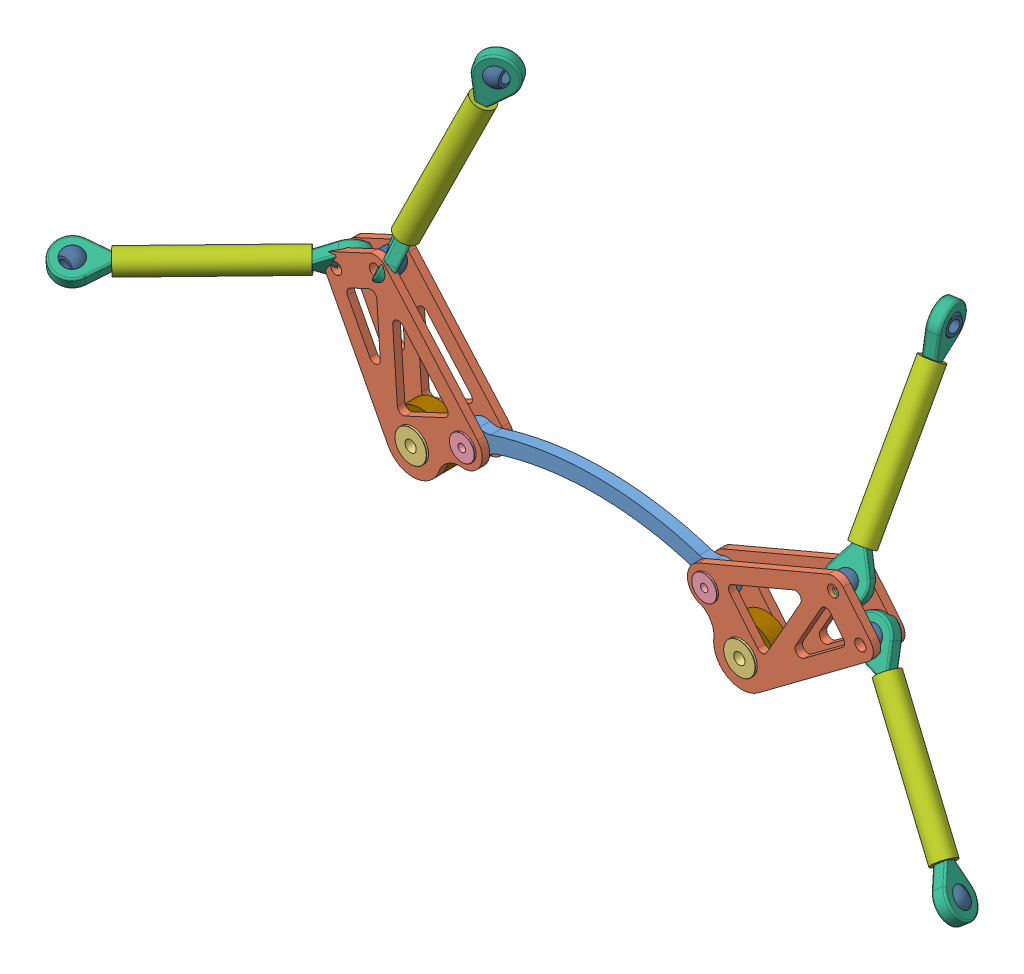
SolidWorks assembly 连杆完整装配, configuration 默认. Lengths in mm.
Overall size (460.39 243.47 165.33).
47 component instances, 10 part files, 72 mates.
Components (placement in the parent):
- 连杆-1: 连杆 [默认] at origin size (146 24.15 6)
- DP_连杆转接板_1 - 副本-1: DP_连杆转接板_1 - 副本 [默认] at (-122.9597 53.5693 -5.5) x (-0.906944 -0.421252 0) z (0 0 1) size (58.5 95 4)
- DP_法兰轴承6x15x5-1: DP_法兰轴承6x15x5 [默认] at (-92.2083 -12.6376 7.7) x (0.813191 0.581997 0) z (0.581997 -0.813191 0) size (17 5 17)
- DP_法兰轴承6x15x5-2: DP_法兰轴承6x15x5 [默认] at (84.0719 -23.1573 7.7) x (0.813191 0.581997 0) z (0.581997 -0.813191 0) size (17 5 17)
- DP_法兰轴承6x15x5-3: DP_法兰轴承6x15x5 [默认] at (-92.2083 -12.6376 -1.7) x (0.663783 0.747925 0) z (-0.747925 0.663783 0) size (17 5 17)
- DP_法兰轴承6x15x5-4: DP_法兰轴承6x15x5 [默认] at (84.0719 -23.1573 -1.7) x (0.621529 0.783391 0) z (-0.783391 0.621529 0) size (17 5 17)
- DP_连杆转接板_1 - 副本-2: DP_连杆转接板_1 - 副本 [默认] at (-122.9597 53.5693 7.5) x (-0.906944 -0.421252 0) z (0 0 1) size (58.5 95 4)
- DP_法兰轴承4x12x4-1: DP_法兰轴承4x12x4 [默认] at (-65 0 8.5) x (0.974596 0.223969 0) z (0.223969 -0.974596 0) size (13.5 4 13.5)
- DP_法兰轴承4x12x4-2: DP_法兰轴承4x12x4 [默认] at (65 0 8.5) x (0.8189 0.573936 0) z (0.573936 -0.8189 0) size (13.5 4 13.5)
- DP_法兰轴承4x12x4-3: DP_法兰轴承4x12x4 [默认] at (65 0 -2.5) x (-0.752362 -0.65875 0) z (0.65875 -0.752362 0) size (13.5 4 13.5)
- DP_法兰轴承4x12x4-4: DP_法兰轴承4x12x4 [默认] at (-65 0 -2.5) x (0.992638 -0.121118 0) z (0.121118 0.992638 0) size (13.5 4 13.5)
- MF84ZZ-1: MF84ZZ [默认] at (-65 0 3.5) x (0 0 1) z (-0.99056 0.137078 0) size (3 9.2 9.2)
- MF84ZZ-2: MF84ZZ [默认] at (65 0 3.5) x (0 0 1) z (-0.982047 0.188634 0) size (3 9.2 9.2)
- MF84ZZ-3: MF84ZZ [默认] at (65 0 2.5) x (0 0 -1) z (0.978579 0.205871 0) size (3 9.2 9.2)
- MF84ZZ-4: MF84ZZ [默认] at (-65 0 2.5) x (0 0 -1) z (0.939447 0.342693 0) size (3 9.2 9.2)
- DP_连杆转接板_1 - 副本-5: DP_连杆转接板_1 - 副本 [默认] at (140.4214 23.2511 11.5) x (0.635732 -0.77191 0) z (0 0 -1) size (58.5 95 4)
- DP_连杆转接板_1 - 副本-6: DP_连杆转接板_1 - 副本 [默认] at (140.4214 23.2511 -1.5) x (0.635732 -0.77191 0) z (0 0 -1) size (58.5 95 4)
- 底盘-连杆系统-1: 底盘-连杆系统 [默认] at (-112.5298 58.4137 3) x (0.523124 -0.035021 0.851537) z (0.360356 0.914535 -0.183765) size (20 20 126) (flexible)
  - 鱼眼轴承M6-1: 鱼眼轴承M6 [默认] at origin size (20 6.75 46)
  - 铝柱 M6-1: 铝柱 M6 [默认] at (0 0 15) x (0.271087 -0.962555 0) z (0 0 1) size (12 12 76)
  - 鱼眼轴承M6-2: 鱼眼轴承M6 [默认] at (0 0 106) x (0 -1 0) z (0 0 -1) size (20 6.75 46)
- 铝合金垫柱4.1D6X2-1: 铝合金垫柱4.1D6X2 [默认] at (65 0 -2.5) size (6 6 2)
- 铝合金垫柱4.1D6X2-2: 铝合金垫柱4.1D6X2 [默认] at (-65 0 -2.5) size (6 6 2)
- 铝合金垫柱4.1D6X2-3: 铝合金垫柱4.1D6X2 [默认] at (65 0 6.5) size (6 6 2)
- 铝合金垫柱4.1D6X2-4: 铝合金垫柱4.1D6X2 [默认] at (-65 0 6.5) size (6 6 2)
- 底盘-连杆系统-2: 底盘-连杆系统 [默认] at (-133.3896 48.7249 3) x (-0.267385 -0.913473 -0.306712) z (-0.718743 -0.022937 0.694898) size (20 20 126) (flexible)
  - 鱼眼轴承M6-1: 鱼眼轴承M6 [默认] at origin size (20 6.75 46)
  - 铝柱 M6-1: 铝柱 M6 [默认] at (0 0 15) x (0.248789 0.968558 0) z (0 0 1) size (12 12 76)
  - 鱼眼轴承M6-2: 鱼眼轴承M6 [默认] at (0 0 106) x (0 -1 0) z (0 0 -1) size (20 6.75 46)
- 底盘-连杆系统-3: 底盘-连杆系统 [默认] at (133.1105 32.1281 3) x (-0.96943 0.077155 0.232923) z (-0.068591 0.826217 -0.559161) size (20 20 126) (flexible)
  - 鱼眼轴承M6-1: 鱼眼轴承M6 [默认] at origin size (20 6.75 46)
  - 铝柱 M6-1: 铝柱 M6 [默认] at (0 0 15) x (-0.636531 -0.771251 0) z (0 0 1) size (12 12 76)
  - 鱼眼轴承M6-2: 鱼眼轴承M6 [默认] at (0 0 106) x (0 -1 0) z (0 0 -1) size (20 6.75 46)
- 底盘-连杆系统-4: 底盘-连杆系统 [默认] at (219.7551 -57.5337 32.6306) x (0.067529 0.437189 0.896831) z (-0.679461 0.678376 -0.279534) size (20 20 126) (flexible)
  - 鱼眼轴承M6-1: 鱼眼轴承M6 [默认] at origin size (20 6.75 46)
  - 铝柱 M6-1: 铝柱 M6 [默认] at (0 0 15) x (0.188345 -0.982103 0) z (0 0 1) size (12 12 76)
  - 鱼眼轴承M6-2: 鱼眼轴承M6 [默认] at (0 0 106) x (0 -1 0) z (0 0 -1) size (20 6.75 46)
- 打印件1-1: 打印件1 [默认] at (84.0719 -23.1573 -1.5) size (30 30 9)
- 打印件1-2: 打印件1 [默认] at (-92.2083 -12.6376 -1.5) size (30 30 9)
- 鱼眼轴承内圈-2: 鱼眼轴承内圈 [默认] at (-133.3896 48.7249 3) x (0 0 -1) z (0.969663 0.244444 0) size (9 12.7 12.7)
- 鱼眼轴承内圈-3: 鱼眼轴承内圈 [默认] at (-112.5298 58.4137 3) x (0 0 1) z (-0.902121 0.431484 0) size (9 12.7 12.7)
- 鱼眼轴承内圈-4: 鱼眼轴承内圈 [默认] at (-74.3322 155.3544 -16.4791) size (9 12.7 12.7)
- 鱼眼轴承内圈-5: 鱼眼轴承内圈 [默认] at (125.8398 119.7071 -56.271) size (9 12.7 12.7)
- 鱼眼轴承内圈-6: 鱼眼轴承内圈 [默认] at (133.1105 32.1281 3) x (0 0 1) z (-0.999574 0.029184 0) size (9 12.7 12.7)
- 鱼眼轴承内圈-7: 鱼眼轴承内圈 [默认] at (147.7323 14.3741 3) x (0 0 1) z (-0.983588 0.18043 0) size (9 12.7 12.7)
- 鱼眼轴承内圈-8: 鱼眼轴承内圈 [默认] at (219.7551 -57.5337 32.6306) x (-0.216884 -0.288424 0.932616) z (-0.939281 0.321897 -0.118883) size (9 12.7 12.7)
- 鱼眼轴承内圈-9: 鱼眼轴承内圈 [默认] at (-209.5763 46.2936 76.6592) x (0 0 -1) z (0.998632 -0.05228 0) size (9 12.7 12.7)
Mates (geometry in assembly coordinates):
- 同心5: concentric aligned: cylinder of DP_连杆转接板_1 - 副本-1 through (-92.2083 -12.6376 -1.5) axis (0 0 -1) radius 7.5; cylinder of DP_连杆转接板_1 - 副本-2 through (-92.2083 -12.6376 11.5) axis (0 0 -1) radius 7.5
- 重合5: coincident aligned: plane of DP_法兰轴承6x15x5-1 through (-89.7687 -10.8916 12.7) normal (0 0 1); plane of DP_法兰轴承6x15x5-2 through (86.5115 -21.4113 12.7) normal (0 0 1)
- 重合6: coincident aligned: plane of DP_法兰轴承6x15x5-3 through (-90.217 -10.3938 -6.7) normal (0 0 -1); plane of DP_法兰轴承6x15x5-4 through (85.9365 -20.8071 -6.7) normal (0 0 -1)
- 重合7: coincident aligned: plane of DP_法兰轴承4x12x4-1 through (-59.1524 1.3438 8.5) normal (0 0 -1); plane of DP_法兰轴承4x12x4-2 through (69.9134 3.4436 8.5) normal (0 0 -1)
- 重合8: coincident aligned: plane of DP_法兰轴承4x12x4-3 through (60.4858 -3.9525 -2.5) normal (0 0 1); plane of DP_法兰轴承4x12x4-4 through (-59.0442 -0.7267 -2.5) normal (0 0 1)
- 同心8: concentric aligned: cylinder of DP_连杆转接板_1 - 副本-1 through (-65 0 -1.5) axis (0 0 -1) radius 6; cylinder of DP_连杆转接板_1 - 副本-2 through (-65 0 11.5) axis (0 0 -1) radius 6
- 同心9: concentric aligned: cylinder of DP_连杆转接板_1 - 副本-2 through (-65 0 11.5) axis (0 0 -1) radius 6; cylinder of DP_法兰轴承4x12x4-1 through (-65 0 8.5) axis (0 0 -1) radius 6
- 重合9: coincident anti-aligned: plane of DP_连杆转接板_1 - 副本-2 through (-112.5298 58.4137 11.5) normal (0 0 1); plane of DP_法兰轴承4x12x4-1 through (-58.4215 1.5118 11.5) normal (0 0 -1)
- 重合11: coincident anti-aligned: plane of DP_连杆转接板_1 - 副本-1 through (-112.5298 58.4137 -5.5) normal (0 0 -1); plane of DP_法兰轴承4x12x4-4 through (-58.2997 -0.8175 -5.5) normal (0 0 1)
- 同心11: concentric anti-aligned: cylinder of DP_连杆转接板_1 - 副本-1 through (-65 0 -1.5) axis (0 0 -1) radius 6; cylinder of DP_法兰轴承4x12x4-4 through (-65 0 -2.5) axis (0 0 1) radius 6
- 重合13: coincident anti-aligned: plane of DP_法兰轴承6x15x5-1 through (-85.2962 -7.6906 11.5) normal (0 0 -1); plane of DP_连杆转接板_1 - 副本-2 through (-112.5298 58.4137 11.5) normal (0 0 1)
- 同心13: concentric aligned: cylinder of DP_法兰轴承6x15x5-1 through (-92.2083 -12.6376 7.7) axis (0 0 -1) radius 7.5; cylinder of DP_连杆转接板_1 - 副本-2 through (-92.2083 -12.6376 11.5) axis (0 0 -1) radius 7.5
- 重合14: coincident anti-aligned: plane of DP_连杆转接板_1 - 副本-1 through (-112.5298 58.4137 -5.5) normal (0 0 -1); plane of DP_法兰轴承6x15x5-3 through (-86.5662 -6.2802 -5.5) normal (0 0 1)
- 同心15: concentric anti-aligned: circle of DP_连杆转接板_1 - 副本-1; circle of DP_法兰轴承6x15x5-3
- 重合15: coincident aligned: plane of MF84ZZ-1 through (-64.7258 1.9811 3.5) normal (0 0 -1); plane of MF84ZZ-2 through (65.3773 1.9641 3.5) normal (0 0 -1)
- 重合16: coincident aligned: plane of MF84ZZ-3 through (64.5883 1.9572 2.5) normal (0 0 1); plane of MF84ZZ-4 through (-65.6854 1.8789 2.5) normal (0 0 1)
- 重合17: coincident anti-aligned: plane of 连杆-1 through (0 0 6) normal (0 0 1); plane of MF84ZZ-2 through (65.7545 3.9282 6) normal (0 0 -1)
- 重合18: coincident anti-aligned: plane of 连杆-1 through (0 0 0) normal (0 0 -1); plane of MF84ZZ-3 through (64.1765 3.9143 0) normal (0 0 1)
- 同心17: concentric anti-aligned: cylinder of 连杆-1 through (-65 0 -9) axis (0 0 1) radius 4; cylinder of MF84ZZ-1 through (-65 0 3.5) axis (0 0 -1) radius 4
- 同心18: concentric anti-aligned: cylinder of 连杆-1 through (65 0 -9) axis (0 0 1) radius 4; cylinder of MF84ZZ-2 through (65 0 3.5) axis (0 0 -1) radius 2
- 同心19: concentric aligned: cylinder of 连杆-1 through (-65 0 -9) axis (0 0 1) radius 4; cylinder of MF84ZZ-4 through (-65 0 2.5) axis (0 0 1) radius 2
- 同心20: concentric aligned: circle of 连杆-1; cylinder of MF84ZZ-3 through (65 0 2.5) axis (0 0 1) radius 2
- 同心21: concentric aligned: cylinder of DP_法兰轴承4x12x4-1 through (-65 0 8.5) axis (0 0 -1) radius 2; cylinder of MF84ZZ-1 through (-65 0 3.5) axis (0 0 -1) radius 2
- 同心22: concentric aligned: cylinder of DP_法兰轴承4x12x4-2 through (65 0 8.5) axis (0 0 -1) radius 2; cylinder of MF84ZZ-2 through (65 0 3.5) axis (0 0 -1) radius 2
- 同心23: concentric anti-aligned: cylinder of DP_法兰轴承4x12x4-2 through (65 0 8.5) axis (0 0 -1) radius 6; cylinder of DP_连杆转接板_1 - 副本-5 through (65 0 7.5) axis (0 0 1) radius 6
- 重合19: coincident anti-aligned: plane of DP_法兰轴承4x12x4-2 through (70.5276 3.8741 11.5) normal (0 0 -1); plane of DP_连杆转接板_1 - 副本-5 through (133.1105 32.1281 11.5) normal (0 0 1)
- 同心24: concentric anti-aligned: cylinder of DP_法兰轴承6x15x5-2 through (84.0719 -23.1573 7.7) axis (0 0 -1) radius 7.5; cylinder of DP_连杆转接板_1 - 副本-5 through (84.0719 -23.1573 7.5) axis (0 0 1) radius 7.5
- 重合20: coincident aligned: plane of DP_连杆转接板_1 - 副本-1 through (-112.5298 58.4137 -1.5) normal (0 0 1); plane of DP_连杆转接板_1 - 副本-6 through (133.1105 32.1281 -1.5) normal (0 0 1)
- 同心25: concentric aligned: cylinder of DP_法兰轴承6x15x5-4 through (84.0719 -23.1573 -1.7) axis (0 0 1) radius 7.5; cylinder of DP_连杆转接板_1 - 副本-6 through (84.0719 -23.1573 -5.5) axis (0 0 1) radius 7.5
- 同心26: concentric aligned: cylinder of DP_法兰轴承4x12x4-3 through (65 0 -2.5) axis (0 0 1) radius 6; cylinder of DP_连杆转接板_1 - 副本-6 through (65 0 -5.5) axis (0 0 1) radius 6
- 同心27: concentric anti-aligned: cylinder of DP_法兰轴承4x12x4-2 through (65 0 8.5) axis (0 0 -1) radius 2; cylinder of DP_法兰轴承4x12x4-3 through (65 0 -2.5) axis (0 0 1) radius 2
- 平行4: parallel anti-aligned: plane of DP_连杆转接板_1 - 副本-2 through (-112.5298 58.4137 7.5) normal (0 0 -1); plane of 底盘-连杆系统-1/鱼眼轴承内圈-2 through (-141.972 13.2403 7.5) normal (0 0 1)
- 重合21: coincident anti-aligned: plane of DP_连杆转接板_1 - 副本-2 through (-112.5298 58.4137 7.5) normal (0 0 -1); plane of 底盘-连杆系统-1/鱼眼轴承内圈-2 through (-141.972 13.2403 7.5) normal (0 0 1)
- 同心28: concentric anti-aligned: cylinder of DP_连杆转接板_1 - 副本-2 through (-112.5298 58.4137 11.5) axis (0 0 -1) radius 3; cylinder of 底盘-连杆系统-1/鱼眼轴承内圈-2 through (-139.7231 9.3654 16.7198) axis (0 0 1) radius 3
- 重合22: coincident anti-aligned: plane of DP_连杆转接板_1 - 副本-1 through (-112.5298 58.4137 -1.5) normal (0 0 1); plane of 底盘-连杆系统-1/鱼眼轴承内圈-2 through (-141.972 13.2403 -1.5) normal (0 0 -1)
- 重合23: coincident aligned: plane of 铝合金垫柱4.1D6X2-3 through (65 0 8.5) normal (0 0 1); plane of 铝合金垫柱4.1D6X2-4 through (-65 0 8.5) normal (0 0 1)
- 重合24: coincident anti-aligned: plane of DP_法兰轴承4x12x4-2 through (69.9134 3.4436 8.5) normal (0 0 -1); plane of 铝合金垫柱4.1D6X2-3 through (65 0 8.5) normal (0 0 1)
- 同心29: concentric anti-aligned: cylinder of DP_法兰轴承4x12x4-2 through (65 0 8.5) axis (0 0 -1) radius 2; circle of 铝合金垫柱4.1D6X2-3
- 同心30: concentric aligned: cylinder of DP_法兰轴承4x12x4-1 through (-65 0 8.5) axis (0 0 -1) radius 2; cylinder of 铝合金垫柱4.1D6X2-4 through (-65 0 8.5) axis (0 0 -1) radius 2.05
- 重合25: coincident aligned: plane of 铝合金垫柱4.1D6X2-1 through (65 0 -0.5) normal (0 0 1); plane of 铝合金垫柱4.1D6X2-2 through (-65 0 -0.5) normal (0 0 1)
- 同心31: concentric anti-aligned: cylinder of DP_法兰轴承4x12x4-4 through (-65 0 -2.5) axis (0 0 1) radius 2; cylinder of 铝合金垫柱4.1D6X2-2 through (-65 0 -0.5) axis (0 0 -1) radius 2.05
- 同心32: concentric anti-aligned: cylinder of DP_法兰轴承4x12x4-3 through (65 0 -2.5) axis (0 0 1) radius 2; cylinder of 铝合金垫柱4.1D6X2-1 through (65 0 -0.5) axis (0 0 -1) radius 3
- 重合26: coincident anti-aligned: plane of DP_法兰轴承4x12x4-4 through (-59.0442 -0.7267 -2.5) normal (0 0 1); plane of 铝合金垫柱4.1D6X2-2 through (-65 0 -2.5) normal (0 0 -1)
- 重合27: coincident anti-aligned: plane of MF84ZZ-4 through (-66.5764 4.3215 -0.5) normal (0 0 -1); plane of 铝合金垫柱4.1D6X2-2 through (-65 0 -0.5) normal (0 0 1)
- 重合28: coincident aligned: plane of 底盘-连杆系统-2/鱼眼轴承内圈-2 through (-150.3509 -8.1791 -1.5) normal (0 0 -1); plane of 底盘-连杆系统-3/鱼眼轴承内圈-2 through (137.2323 15.0015 -1.5) normal (0 0 -1)
- 重合29: coincident aligned: plane of 底盘-连杆系统-3/鱼眼轴承内圈-2 through (137.2323 15.0015 -1.5) normal (0 0 -1); plane of 底盘-连杆系统-4/鱼眼轴承内圈-2 through (146.1145 -6.2142 -1.5) normal (0 0 -1)
- 重合30: coincident anti-aligned: plane of DP_连杆转接板_1 - 副本-1 through (-112.5298 58.4137 -1.5) normal (0 0 1); plane of 底盘-连杆系统-2/鱼眼轴承内圈-2 through (-150.3509 -8.1791 -1.5) normal (0 0 -1)
- 同心33: concentric anti-aligned: cylinder of DP_连杆转接板_1 - 副本-1 through (-133.3896 48.7249 -1.5) axis (0 0 -1) radius 3; cylinder of 底盘-连杆系统-2/鱼眼轴承内圈-2 through (-148.102 -12.0541 16.7198) axis (0 0 1) radius 3
- 同心34: concentric aligned: cylinder of DP_连杆转接板_1 - 副本-5 through (133.1105 32.1281 7.5) axis (0 0 1) radius 3; cylinder of 底盘-连杆系统-3/鱼眼轴承内圈-2 through (139.4812 11.1266 16.7198) axis (0 0 1) radius 3
- 同心35: concentric anti-aligned: cylinder of DP_法兰轴承6x15x5-2 through (84.0719 -23.1573 7.7) axis (0 0 -1) radius 3; cylinder of DP_法兰轴承6x15x5-4 through (84.0719 -23.1573 -1.7) axis (0 0 1) radius 3
- 同心36: concentric aligned: cylinder of DP_连杆转接板_1 - 副本-6 through (147.7323 14.3741 -5.5) axis (0 0 1) radius 3; cylinder of 底盘-连杆系统-4/鱼眼轴承内圈-2 through (148.3634 -10.0891 16.7198) axis (0 0 1) radius 3
- 重合31: coincident aligned: plane of 打印件1-1 through (84.0719 -23.1573 7.5) normal (0 0 1); plane of 打印件1-2 through (-92.2083 -12.6376 7.5) normal (0 0 1)
- 重合32: coincident anti-aligned: plane of DP_连杆转接板_1 - 副本-5 through (133.1105 32.1281 7.5) normal (0 0 -1); plane of 打印件1-1 through (84.0719 -23.1573 7.5) normal (0 0 1)
- 同心37: concentric aligned: cylinder of DP_法兰轴承6x15x5-2 through (84.0719 -23.1573 7.7) axis (0 0 -1) radius 3; cylinder of 打印件1-1 through (84.0719 -23.1573 7.5) axis (0 0 -1) radius 15
- 同心38: concentric aligned: cylinder of DP_法兰轴承6x15x5-1 through (-92.2083 -12.6376 7.7) axis (0 0 -1) radius 3; cylinder of 打印件1-2 through (-92.2083 -12.6376 7.5) axis (0 0 -1) radius 15
- 同心40: concentric: sphere of 底盘-连杆系统-2/鱼眼轴承M6-1; sphere of 鱼眼轴承内圈-2
- 同心41: concentric: sphere of 底盘-连杆系统-1/鱼眼轴承M6-2; sphere of 鱼眼轴承内圈-4
- 同心42: concentric: sphere of 底盘-连杆系统-1/鱼眼轴承M6-1; sphere of 鱼眼轴承内圈-3
- 重合34: coincident anti-aligned: plane of MF84ZZ-1 through (-64.3694 4.5566 6.5) normal (0 0 1); plane of 铝合金垫柱4.1D6X2-4 through (-65 0 6.5) normal (0 0 -1)
- 重合35: coincident anti-aligned: plane of DP_连杆转接板_1 - 副本-2 through (-112.5298 58.4137 7.5) normal (0 0 -1); plane of 鱼眼轴承内圈-2 through (-134.4847 53.0693 7.5) normal (0 0 1)
- 同心44: concentric anti-aligned: cylinder of DP_连杆转接板_1 - 副本-2 through (-133.3896 48.7249 11.5) axis (0 0 -1) radius 3; cylinder of 鱼眼轴承内圈-2 through (-133.3896 48.7249 16.7198) axis (0 0 1) radius 3
- 同心45: concentric aligned: cylinder of DP_连杆转接板_1 - 副本-2 through (-112.5298 58.4137 11.5) axis (0 0 -1) radius 3; cylinder of 鱼眼轴承内圈-3 through (-112.5298 58.4137 -10.7198) axis (0 0 -1) radius 3
- 重合36: coincident anti-aligned: plane of DP_连杆转接板_1 - 副本-2 through (-112.5298 58.4137 7.5) normal (0 0 -1); plane of 鱼眼轴承内圈-3 through (-110.5967 62.4554 7.5) normal (0 0 1)
- 同心46: concentric: sphere of 底盘-连杆系统-2/鱼眼轴承M6-2; sphere of 鱼眼轴承内圈-9
- 同心47: concentric: sphere of 底盘-连杆系统-4/鱼眼轴承M6-1; sphere of 鱼眼轴承内圈-8
- 同心48: concentric: sphere of 底盘-连杆系统-4/鱼眼轴承M6-2; sphere of 鱼眼轴承内圈-7
- 重合37: coincident anti-aligned: plane of DP_连杆转接板_1 - 副本-5 through (133.1105 32.1281 7.5) normal (0 0 -1); plane of 鱼眼轴承内圈-7 through (148.5407 18.7808 7.5) normal (0 0 1)
- 同心49: concentric anti-aligned: cylinder of DP_连杆转接板_1 - 副本-6 through (147.7323 14.3741 -5.5) axis (0 0 1) radius 3; cylinder of 鱼眼轴承内圈-7 through (147.7323 14.3741 -10.7198) axis (0 0 -1) radius 3
- 同心50: concentric: sphere of 底盘-连杆系统-3/鱼眼轴承M6-1; sphere of 鱼眼轴承内圈-6
- 同心51: concentric: sphere of 底盘-连杆系统-3/鱼眼轴承M6-2; sphere of 鱼眼轴承内圈-5
- 重合38: coincident anti-aligned: plane of DP_连杆转接板_1 - 副本-5 through (133.1105 32.1281 7.5) normal (0 0 -1); plane of 鱼眼轴承内圈-6 through (133.2412 36.6064 7.5) normal (0 0 1)
- 同心52: concentric anti-aligned: cylinder of DP_连杆转接板_1 - 副本-5 through (133.1105 32.1281 7.5) axis (0 0 1) radius 3; cylinder of 鱼眼轴承内圈-6 through (133.1105 32.1281 -10.7198) axis (0 0 -1) radius 3
